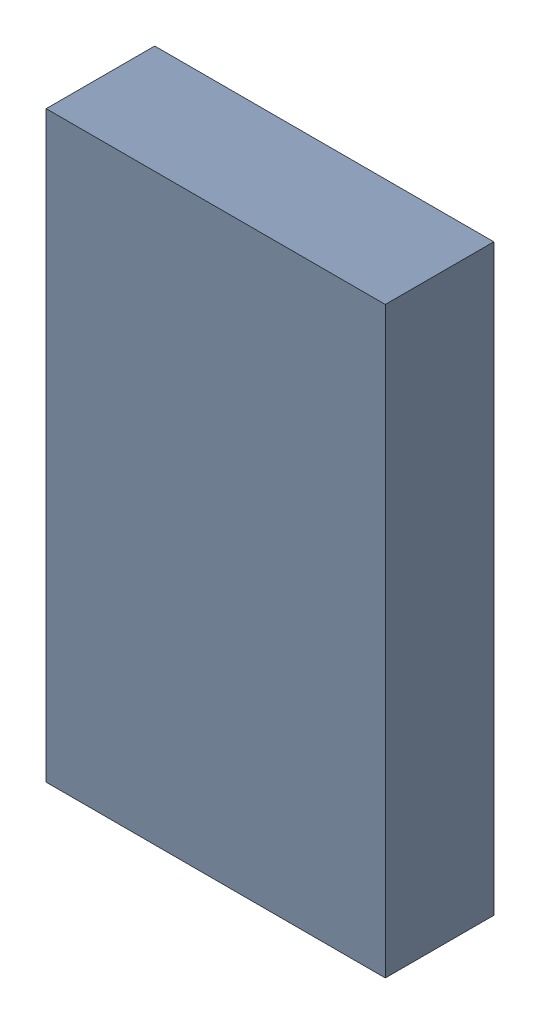
SolidWorks assembly Free-Models, configuration Standard. Lengths in mm.
Overall size (25 43 8).
2 component instances, 1 part files, 0 mates.
Components (placement in the parent):
- 6074061104-1: 6074061104 [Standard] at (-3.5 -2.5 -9.6224) size (25 43 8)
  - Extruded-1: Extruded [Standard] at origin size (25 43 8)
